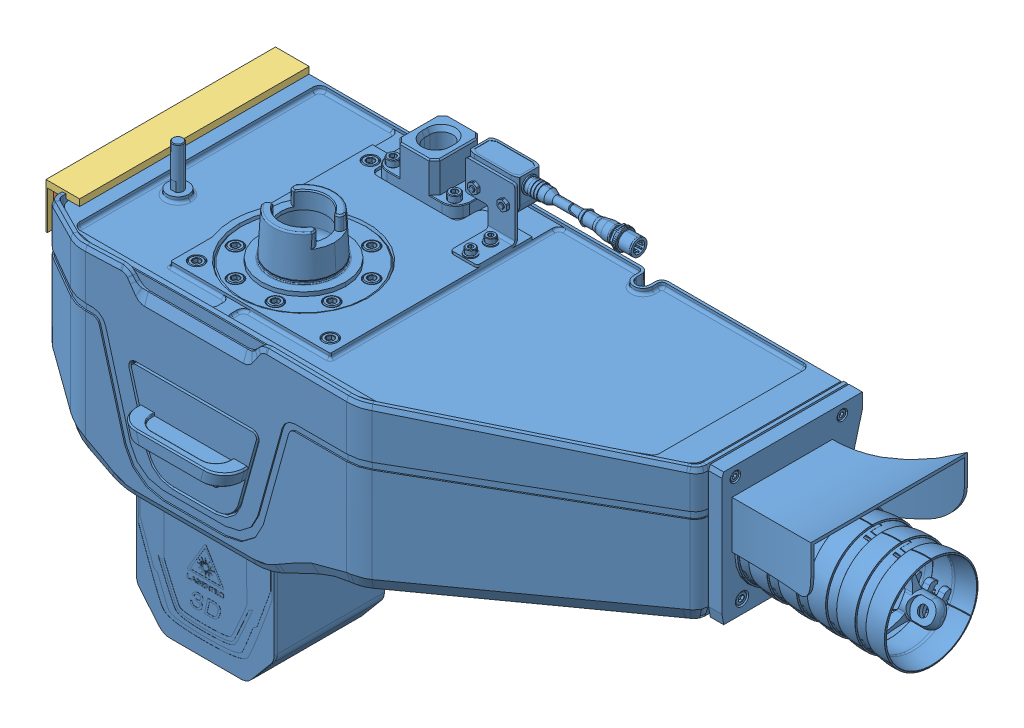
SolidWorks assembly AssemLblock, configuration Default. Lengths in mm.
Overall size (559.54 264.1 223.32).
3 component instances, 3 part files, 2 mates.
Components (placement in the parent):
- LASER_BASEHEAD_COAX9_SW2018-1: LASER_BASEHEAD_COAX9_SW2018 [Default] at origin size (548.59 264.1 223.32)
- LasertecMountingPlate_HOLEMOD-1: LasertecMountingPlate_HOLEMOD [Default] at (186.9473 174 -123.6003) x (0 0 1) z (-1 0 0) size (167 162.5 15)
- Lblock-1: Lblock [Default] at (171.9473 0 0) x (0 0 1) z (-1 0 0) size (171.68 33.97 25.15)
Mates (geometry in assembly coordinates):
- Coincident8: coincident anti-aligned: plane of LASER_BASEHEAD_COAX9_SW2018-1 through (186.9473 262.5 -156.1003) normal (-1 0 0); plane of LasertecMountingPlate_HOLEMOD-1 through (186.9473 174 -123.6003) normal (1 0 0)
- Coincident13: coincident anti-aligned: line of LasertecMountingPlate_HOLEMOD-1 through (171.9473 272.5 -223.1003) axis (1 0 0); line of Lblock-1 through (196.0988 272.5 -223.1003) axis (-1 0 0)
